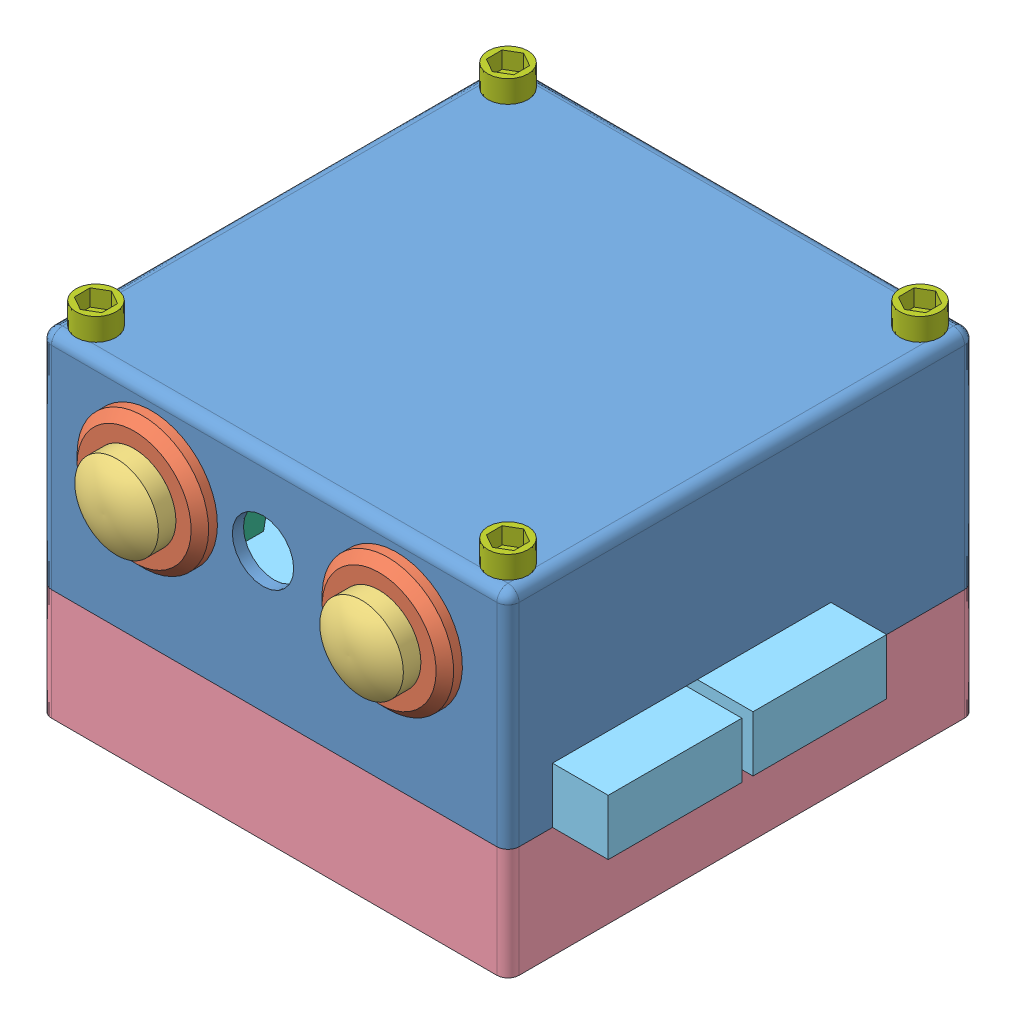
SolidWorks assembly touch dro rev 2, configuration Default. Lengths in mm.
Overall size (63.5 40.64 60.19).
15 component instances, 7 part files, 20 mates.
Components (placement in the parent):
- touch dro top rev 2-1: touch dro top rev 2 [Default] at (-14.0119 15.5279 67.2051) size (53.34 25.4 53.34)
- ds-228-1: ds-228 [Default] at (-6.9733 18.7017 74.5773) x (-0.923728 -0.383049 0) z (0 0 -1) size (15 15 23.05)
  - button case-1: button case [Default] at (-8.9217 10.0503 23.6022) size (15 15 19.5)
  - button cap-1: button cap [Default] at (-8.9217 10.0503 4.1022) x (1 0 0) z (0 1 0) size (9.53 3.55 9.53)
- ds-228-2: ds-228 [Default] at (16.466 41.4794 74.5773) x (0.121477 0.992594 0) z (0 0 -1) size (15 15 23.05)
  - button case-1: button case [Default] at (-8.9217 10.0503 23.6022) size (15 15 19.5)
  - button cap-1: button cap [Default] at (-8.9217 10.0503 4.1022) x (1 0 0) z (0 1 0) size (9.53 3.55 9.53)
- touch dro bottom rev 2-1: touch dro bottom rev 2 [Default] at (-14.0119 15.5279 67.2051) size (53.34 12.7 53.34)
- pcb-1: pcb [Default] at (-14.0119 14.2579 67.2051) size (63.5 20.32 53.37)
- button nut-1: button nut [Default] at (25.3581 31.4029 62.2051) x (0.877524 -0.479532 0) z (-0.479532 -0.877524 0) size (15.98 5 15.3)
- button nut-2: button nut [Default] at (-2.5819 31.4029 62.2051) x (-0.863261 0.504758 0) z (0.504758 0.863261 0) size (15.98 5 15.3)
- 4-40 x 1.25-1: 4-40 x 1.25 [Default] at (-12.1069 9.1779 18.3101) x (1 0 0) z (0 1 0) size (4.57 4.57 34.29)
- 4-40 x 1.25-2: 4-40 x 1.25 [Default] at (34.8831 9.1779 65.3001) x (1 0 0) z (0 1 0) size (4.57 4.57 34.29)
- 4-40 x 1.25-3: 4-40 x 1.25 [Default] at (34.8831 9.1779 18.3101) x (1 0 0) z (0 1 0) size (4.57 4.57 34.29)
- 4-40 x 1.25-4: 4-40 x 1.25 [Default] at (-12.1069 9.1779 65.3001) x (1 0 0) z (0 1 0) size (4.57 4.57 34.29)
Mates (geometry in assembly coordinates):
- Concentric1: concentric aligned: cylinder of touch dro top rev 2-1 through (-2.5819 31.4029 68.4751) axis (0 0 1) radius 6.7462; cylinder of ds-228-1/button case-1 through (-2.5819 31.4029 70.4751) axis (0 0 1) radius 6.35
- Coincident2: coincident anti-aligned: plane of touch dro top rev 2-1 through (-15.2819 40.9279 68.4751) normal (0 0 1); plane of ds-228-1/button case-1 through (-8.4476 28.9706 68.4751) normal (0 0 -1)
- Concentric2: concentric aligned: cylinder of touch dro top rev 2-1 through (25.3581 31.4029 68.4751) axis (0 0 1) radius 6.7462; cylinder of ds-228-2/button case-1 through (25.3581 31.4029 70.4751) axis (0 0 1) radius 6.35
- Coincident3: coincident anti-aligned: plane of touch dro top rev 2-1 through (-15.2819 40.9279 68.4751) normal (0 0 1); plane of ds-228-2/button case-1 through (26.1295 37.7059 68.4751) normal (0 0 -1)
- Concentric5: concentric anti-aligned: cylinder of touch dro bottom rev 2-1 through (-12.1069 15.5279 18.3101) axis (0 1 0) radius 1.1303; cylinder of pcb-1 through (-12.1069 15.5289 18.3101) axis (0 -1 0) radius 1.1
- Coincident4: coincident anti-aligned: plane of touch dro bottom rev 2-1 through (-14.0119 14.2579 67.2051) normal (0 1 0); plane of pcb-1 through (-14.0119 14.2579 67.2051) normal (0 -1 0)
- Coincident5: coincident anti-aligned: plane of touch dro top rev 2-1 through (-14.0119 15.5279 67.2051) normal (0 -1 0); plane of touch dro bottom rev 2-1 through (-14.0119 15.5279 67.2051) normal (0 1 0)
- Concentric6: concentric aligned: cylinder of touch dro top rev 2-1 through (34.8831 10.2116 65.3001) axis (0 1 0) radius 1.4732; cylinder of touch dro bottom rev 2-1 through (34.8831 15.5279 65.3001) axis (0 1 0) radius 1.1303
- Concentric7: concentric anti-aligned: cylinder of ds-228-2/button case-1 through (25.3581 31.4029 70.4751) axis (0 0 1) radius 6.35; cylinder of button nut-1 through (25.3581 31.4029 67.2051) axis (0 0 -1) radius 6.35
- Coincident11: coincident anti-aligned: plane of touch dro top rev 2-1 through (-15.2819 40.9279 67.2051) normal (0 0 -1); plane of button nut-1 through (25.3581 31.4029 67.2051) normal (0 0 1)
- Concentric8: concentric anti-aligned: cylinder of ds-228-1/button case-1 through (-2.5819 31.4029 70.4751) axis (0 0 1) radius 6.35; cylinder of button nut-2 through (-2.5819 31.4029 67.2051) axis (0 0 -1) radius 6.35
- Coincident12: coincident anti-aligned: plane of touch dro top rev 2-1 through (-15.2819 40.9279 67.2051) normal (0 0 -1); plane of button nut-2 through (-2.5819 31.4029 67.2051) normal (0 0 1)
- Concentric9: concentric anti-aligned: cylinder of touch dro top rev 2-1 through (-12.1069 10.2116 18.3101) axis (0 1 0) radius 1.4732; cylinder of 4-40 x 1.25-1 through (-12.1069 40.9279 18.3101) axis (0 -1 0) radius 1.397
- Coincident13: coincident anti-aligned: plane of touch dro top rev 2-1 through (-14.0119 40.9279 67.2051) normal (0 1 0); plane of 4-40 x 1.25-1 through (-12.1069 40.9279 18.3101) normal (0 -1 0)
- Concentric10: concentric anti-aligned: cylinder of touch dro top rev 2-1 through (34.8831 10.2116 18.3101) axis (0 1 0) radius 1.4732; cylinder of 4-40 x 1.25-3 through (34.8831 40.9279 18.3101) axis (0 -1 0) radius 1.397
- Coincident14: coincident anti-aligned: plane of touch dro top rev 2-1 through (-14.0119 40.9279 67.2051) normal (0 1 0); plane of 4-40 x 1.25-3 through (34.8831 40.9279 18.3101) normal (0 -1 0)
- Concentric11: concentric anti-aligned: cylinder of touch dro top rev 2-1 through (-12.1069 10.2116 65.3001) axis (0 1 0) radius 1.4732; cylinder of 4-40 x 1.25-4 through (-12.1069 40.9279 65.3001) axis (0 -1 0) radius 1.397
- Coincident15: coincident anti-aligned: plane of touch dro top rev 2-1 through (-14.0119 40.9279 67.2051) normal (0 1 0); plane of 4-40 x 1.25-4 through (-12.1069 40.9279 65.3001) normal (0 -1 0)
- Concentric12: concentric anti-aligned: cylinder of touch dro top rev 2-1 through (34.8831 10.2116 65.3001) axis (0 1 0) radius 1.4732; cylinder of 4-40 x 1.25-2 through (34.8831 40.9279 65.3001) axis (0 -1 0) radius 1.397
- Coincident16: coincident anti-aligned: plane of touch dro top rev 2-1 through (-14.0119 40.9279 67.2051) normal (0 1 0); plane of 4-40 x 1.25-2 through (34.8831 40.9279 65.3001) normal (0 -1 0)
